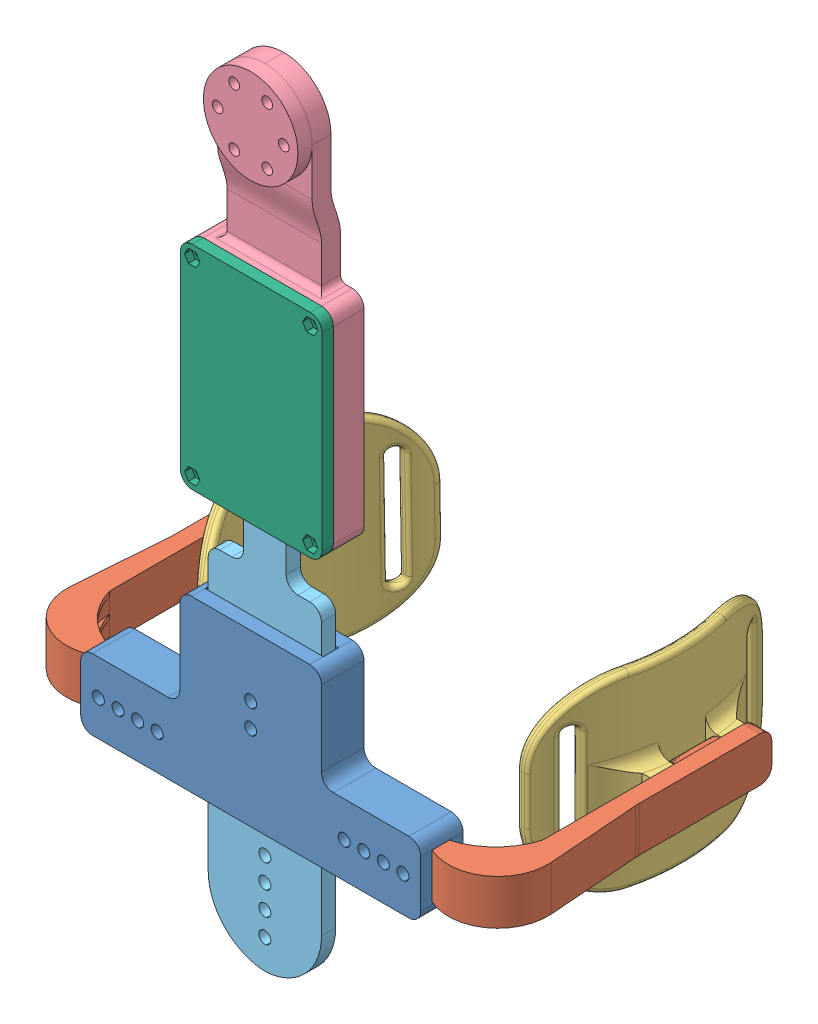
SolidWorks assembly New_Exo_Banu, configuration Default. Lengths in mm.
Overall size (204.15 333.03 153.56).
8 component instances, 6 part files, 16 mates.
Components (placement in the parent):
- ThighTShape_v2-1: ThighTShape_v2 [Default] at (49.892 -65.755 95.8094) size (144 72 18)
- Lshape-thigh_running-1: Lshape-thigh_running [Default] at (148.6212 -95.755 -8.1906) x (0 0 1) z (-1 0 0) size (120 19 90.06)
- Lshape-thigh_running-2: Lshape-thigh_running [Default] at (-49.4106 -77.755 -8.6906) x (0 0 1) z (1 0 0) size (120 19 90.06)
- slide1WideV3-1: slide1WideV3 [Default] at (45.6212 -126.755 11.3174) x (0 0 1) z (-1 0 0) size (102.14 80 33)
- slide1WideV3-2: slide1WideV3 [Default] at (54.228 -125.2695 21.5769) x (0 0 -1) z (0.999868 0.016266 0) size (102.14 80 33)
- RotorAttachCanted_v4_hinge_removed_8mm-2: RotorAttachCanted_v4_hinge_removed_8mm [Default] at (49.892 155.2469 113.8094) x (-1 0 0) z (0 0 -1) size (60 166 18)
- ThighVertAdjust_v2-1: ThighVertAdjust_v2 [Default] at (49.892 -157.7992 104.8094) size (48 224.98 6)
- RotorAttachCanted_top_cover-1: RotorAttachCanted_top_cover [Default] at (49.892 54.2469 113.5719) x (-1 0 0) z (0 0 -1) size (60 90 4.76)
Mates (geometry in assembly coordinates):
- Distance6: distance = 0.25 mm anti-aligned: plane of ThighTShape_v2-1 through (20.392 -76.755 108.5594) normal (0 0 -1); plane of Lshape-thigh_running-2 through (-22.4106 -96.755 108.3094) normal (0 0 1)
- Distance7: distance = 1 mm anti-aligned: plane of ThighTShape_v2-1 through (20.392 -76.755 101.0594) normal (0 -1 0); plane of Lshape-thigh_running-2 through (-22.4106 -77.755 81.3094) normal (0 1 0)
- Distance8: distance = 0.25 mm anti-aligned: plane of Lshape-thigh_running-1 through (121.6212 -76.755 108.8094) normal (0 0 1); plane of ThighTShape_v2-1 through (79.392 -76.755 108.5594) normal (0 0 -1)
- Coincident11: coincident anti-aligned: plane of ThighTShape_v2-1 through (79.392 -76.755 101.0594) normal (0 -1 0); plane of Lshape-thigh_running-1 through (121.6212 -76.755 81.8094) normal (0 1 0)
- Parallel8: parallel anti-aligned: plane of ThighTShape_v2-1 through (74.892 -101.755 101.5594) normal (-1 0 0); plane of ThighVertAdjust_v2-1 through (73.892 67.2008 101.8094) normal (1 0 0)
- Distance9: distance = 1 mm anti-aligned: plane of ThighTShape_v2-1 through (24.892 -101.755 101.5594) normal (1 0 0); plane of ThighVertAdjust_v2-1 through (25.892 67.2008 101.8094) normal (-1 0 0)
- Distance10: distance = 0.25 mm anti-aligned: plane of ThighVertAdjust_v2-1 through (25.892 67.2008 107.8094) normal (0 0 1); plane of ThighTShape_v2-1 through (24.892 -101.755 108.0594) normal (0 0 -1)
- Distance11: distance = 1 mm anti-aligned: plane of RotorAttachCanted_v4_hinge_removed_8mm-2 through (24.892 89.2469 100.8094) normal (0 0 1); plane of ThighVertAdjust_v2-1 through (25.892 67.2008 101.8094) normal (0 0 -1)
- Parallel9: parallel anti-aligned: plane of RotorAttachCanted_v4_hinge_removed_8mm-2 through (74.892 89.2469 108.8094) normal (-1 0 0); plane of ThighVertAdjust_v2-1 through (73.892 67.2008 101.8094) normal (1 0 0)
- Distance14: distance = 1 mm anti-aligned: plane of ThighVertAdjust_v2-1 through (25.892 67.2008 101.8094) normal (-1 0 0); plane of RotorAttachCanted_v4_hinge_removed_8mm-2 through (24.892 89.2469 108.8094) normal (1 0 0)
- Coincident31: coincident anti-aligned: plane of RotorAttachCanted_v4_hinge_removed_8mm-2 through (49.892 155.2469 108.8094) normal (0 0 1); plane of RotorAttachCanted_top_cover-1 through (49.892 54.2469 108.8094) normal (0 0 -1)
- Coincident32: coincident aligned: plane of RotorAttachCanted_v4_hinge_removed_8mm-2 through (19.892 9.2469 113.8094) normal (-1 0 0); plane of RotorAttachCanted_top_cover-1 through (19.892 9.2469 108.8094) normal (-1 0 0)
- Coincident33: coincident aligned: plane of RotorAttachCanted_v4_hinge_removed_8mm-2 through (49.892 9.2469 113.8094) normal (0 -1 0); plane of RotorAttachCanted_top_cover-1 through (19.892 9.2469 108.8094) normal (0 -1 0)
- Parallel11: parallel aligned: plane of RotorAttachCanted_v4_hinge_removed_8mm-2 through (24.892 89.2469 100.8094) normal (0 0 1); plane of RotorAttachCanted_top_cover-1 through (49.892 54.2469 113.5719) normal (0 0 1)
- Concentric2: concentric aligned: cylinder of Lshape-thigh_running-2 through (-37.4106 -86.755 20.3094) axis (0 0 -1) radius 2.15; cylinder of slide1WideV3-2 through (-37.4106 -86.755 47.3752) axis (0 0 -1) radius 2.05
- Concentric3: concentric anti-aligned: cylinder of Lshape-thigh_running-1 through (136.6212 -86.755 20.8094) axis (0 0 -1) radius 2.15; cylinder of slide1WideV3-1 through (136.6212 -86.755 -14.4809) axis (0 0 1) radius 2.05
